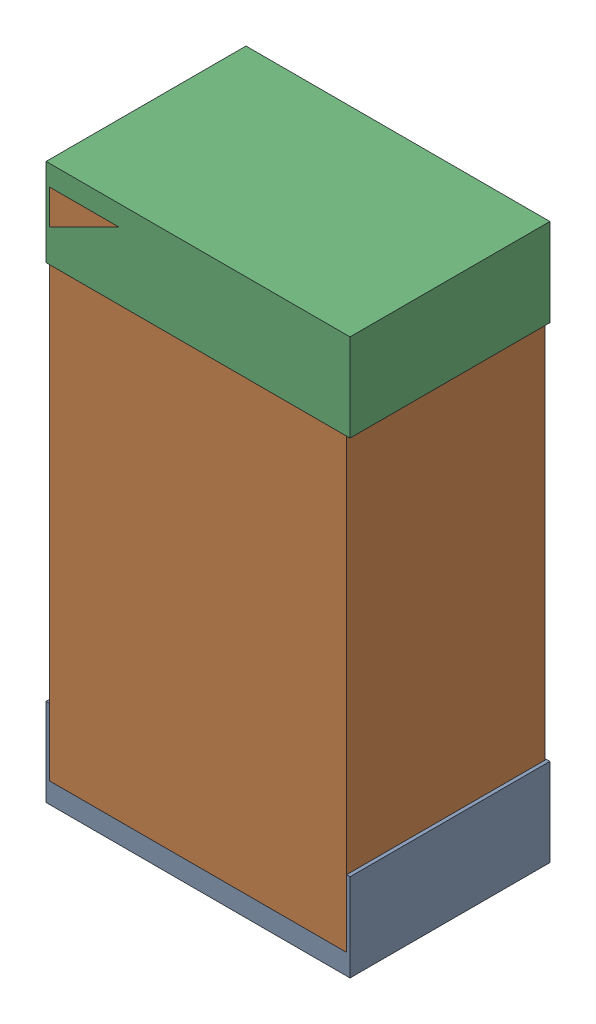
SolidWorks assembly R35Kanaloa_v2.0.0_Motor, configuration Default. Lengths in mm.
Overall size (1.3 2.38 0.85).
6 component instances, 2 part files, 0 mates.
Components (placement in the parent):
- 330415056-1: 330415056 [Default] at (41.402 118.575 -1.9574) size (1.3 0.38 0.85)
  - Extruded_2-1: Extruded_2 [Default] at origin size (1.3 0.38 0.85)
- 334787376-1: 334787376 [Default] at (41.402 119.575 -1.9524) size (1.27 2.2 0.85)
  - Extruded_16-1: Extruded_16 [Default] at origin size (1.27 2.2 0.85)
- 330415056-2: 330415056 [Default] at (41.402 120.575 -1.9574) size (1.3 0.38 0.85)
  - Extruded_2-1: Extruded_2 [Default] at origin size (1.3 0.38 0.85)
